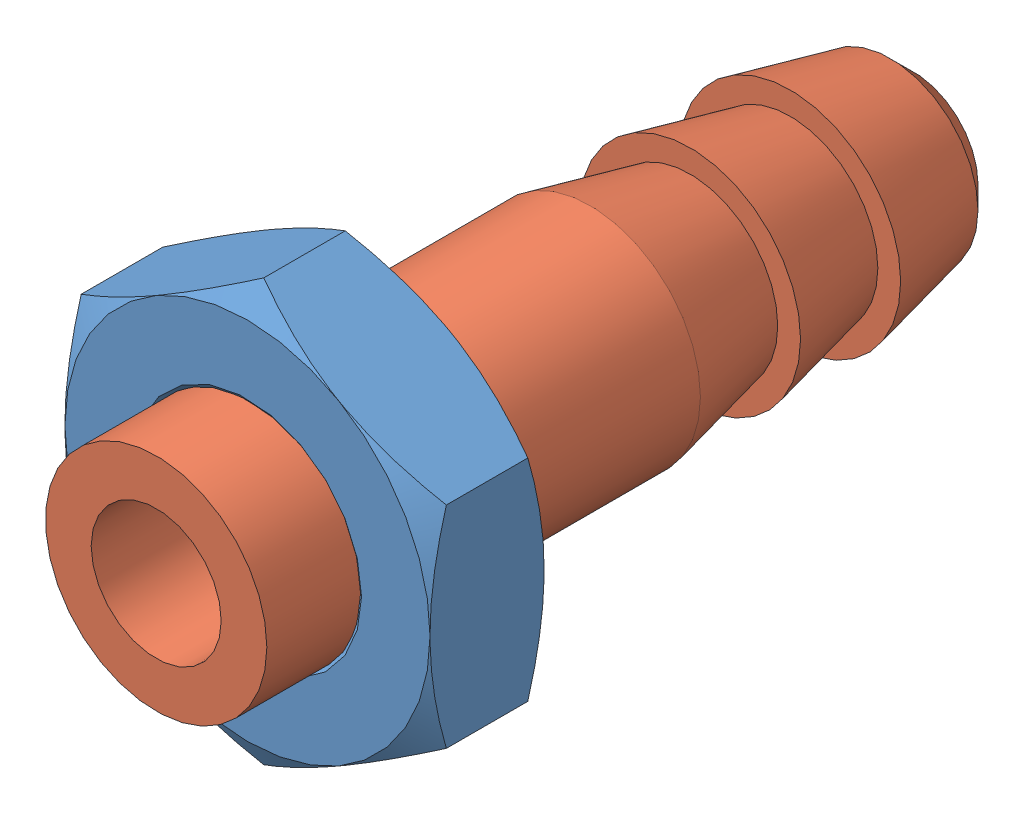
SolidWorks assembly silta_letkukara_assy, configuration Default. Lengths in mm.
Overall size (16 18.48 33.16).
2 component instances, 2 part files, 2 mates.
Components (placement in the parent):
- Hexagon Thin Nut ISO - 4035 - M10 - N-1: Hexagon Thin Nut ISO - 4035 - M10 - N [Hexagon Thin Nut ISO - 4035 - M10 - N] at (2.7846 12.3711 -7.3742) size (16 18.48 5)
- silta_letkukara-1: silta_letkukara [Default] at (-2.0654 12.3711 -3.3742) size (9.7 9.7 33.16)
Mates (geometry in assembly coordinates):
- Concentric1: concentric aligned: cylinder of Hexagon Thin Nut ISO - 4035 - M10 - N-1 through (2.7846 12.3711 -12.3742) axis (0 0 1) radius 4.25; cylinder of silta_letkukara-1 through (2.7846 12.3711 -3.3742) axis (0 0 1) radius 4.85
- Distance1: distance = 4 mm aligned: plane of Hexagon Thin Nut ISO - 4035 - M10 - N-1 through (-13.2154 12.3711 -7.3742) normal (0 0 1); plane of silta_letkukara-1 through (-2.0654 12.3711 -3.3742) normal (0 0 1)
